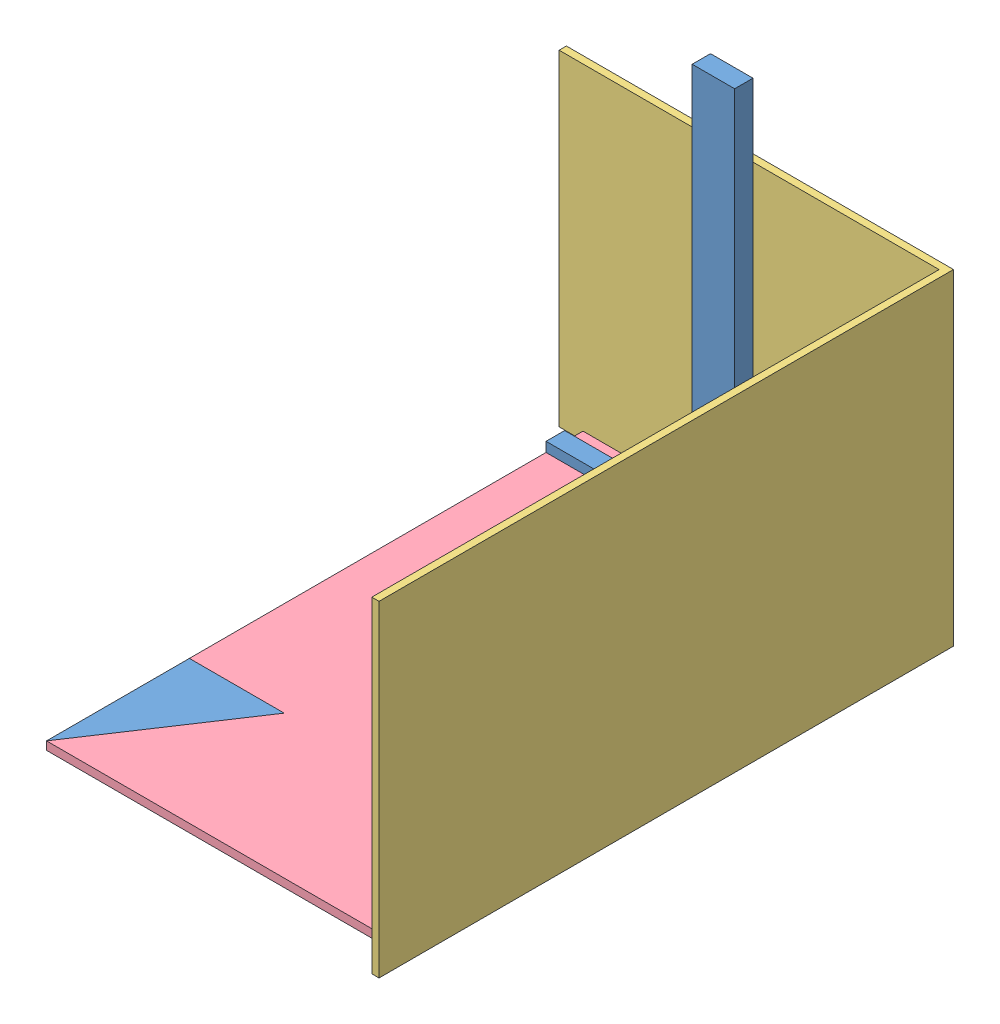
SolidWorks assembly tabletop_link_simple, configuration Default. Lengths in mm.
Overall size (800.31 824.4 1187.5).
4 component instances, 4 part files, 9 mates.
Components (placement in the parent):
- plywood_simple-1: plywood_simple [Default] at origin size (609 824.4 1108.7)
- PowerSupply-1: PowerSupply [Default] at (241.3 17 -266.3) x (-1 0 0) z (0 1 0) size (145 157 87)
- Wall-1: Wall [Default] at (85.6891 0 24.7806) size (800.31 674.14 1187.5)
- SimplifiedPlane-1: SimplifiedPlane [Default] at (0 0 710.27) size (736 17 1108.7)
Mates (geometry in assembly coordinates):
- Coincident3: coordinate: point of plywood_simple-1; point of assembly
- Coincident14: coincident anti-aligned: plane of plywood_simple-1 through (304 37 -322.03) normal (0 0 1); plane of PowerSupply-1 through (-63.7 104 -322.03) normal (0 0 -1)
- Coincident15: coincident anti-aligned: plane of plywood_simple-1 through (-305 17 710.27) normal (0 1 0); plane of PowerSupply-1 through (-63.7 17 -165.03) normal (0 -1 0)
- Distance3: distance = 241.3 mm aligned: plane of PowerSupply-1 through (-63.7 104 -322.03) normal (-1 0 0); plane of plywood_simple-1 through (-305 696.8839 -360.53) normal (-1 0 0)
- Coincident17: coincident anti-aligned: plane of plywood_simple-1 through (-41.475 824.4 -398.43) normal (0 0 -1); plane of Wall-1 through (431 674.1356 -398.43) normal (0 0 1)
- InPlace1: in place: plane of plywood_simple-1 through (-305 17 710.27) normal (0 0 1); plane of SimplifiedPlane-1 through (0 0 710.27) normal (0 0 1); moOrthogonalPlaneRef_w of plywood_simple-1 through (-305 17 710.27) normal (0 0 1); plane of SimplifiedPlane-1 through (0 0 710.27) normal (0 1 0); plane of plywood_simple-1 through (-305 17 710.27) normal (0 0 1); plane of SimplifiedPlane-1 through (0 0 710.27) normal (1 0 0); plane of plywood_simple-1 through (-305 17 710.27) normal (0 0 1); unknown of SimplifiedPlane-1
- Coincident18: coincident aligned: plane of plywood_simple-1; plane of SimplifiedPlane-1
- Coincident19: coincident aligned: moOrthogonalPlaneRef_w of plywood_simple-1 through (0 0 710.27) normal (0 1 0); plane of SimplifiedPlane-1 through (0 0 710.27) normal (0 1 0)
- Coincident20: coincident anti-aligned: moOrthogonalPlaneRef_w of plywood_simple-1 through (0 0 710.27) normal (-1 0 0); plane of SimplifiedPlane-1 through (0 0 710.27) normal (1 0 0)
